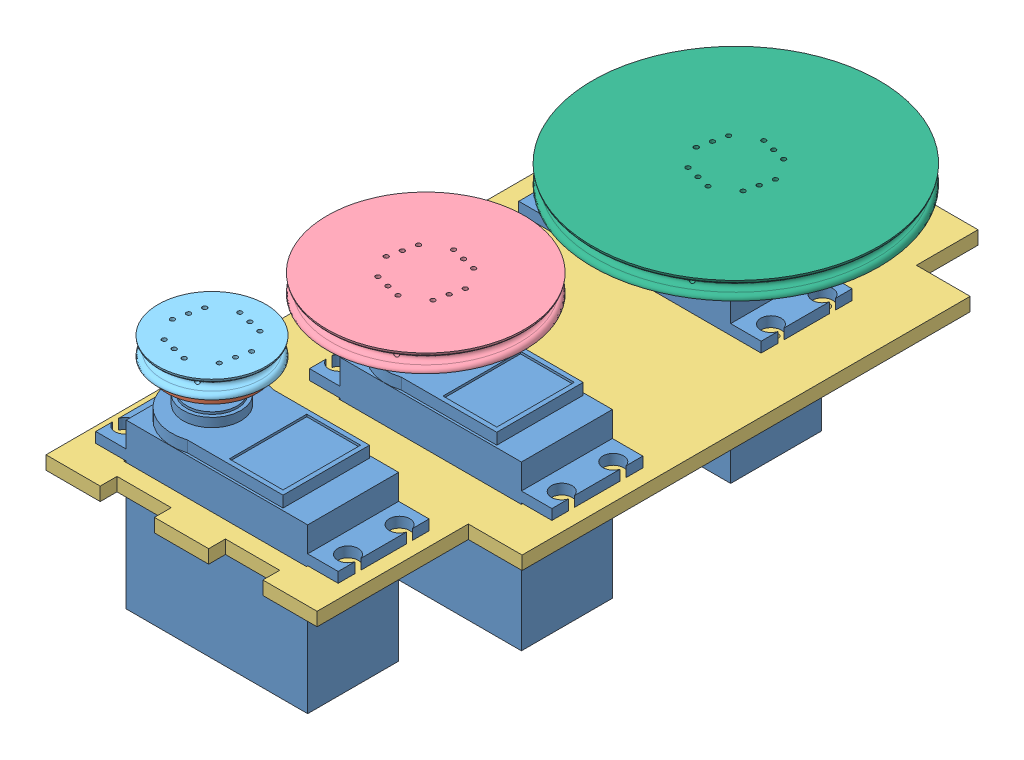
SolidWorks assembly ServoSet, configuration Default. Lengths in mm.
Overall size (82.84 52.3 148.09).
13 component instances, 6 part files, 18 mates.
Components (placement in the parent):
- MG996R-Servo-with-Hub-1: MG996R-Servo-with-Hub [Default] at (-42.4416 98.8668 240.9659) x (0 0 -1) z (1 0 0) size (24.11 48.3 54.1)
  - MG996R-Servo-1: MG996R-Servo [Default] at (29.3026 10.0421 49.0781) size (20.3 45.5 54.1)
  - Servo-Hub-1: Servo-Hub [Default] at (29.3026 56.1421 60.3281) x (0.973354 0 0.229307) z (-0.229307 0 0.973354) size (20.05 5.6 20.05)
- ServoHolderDirect-2: ServoHolderDirect [Default] at (3.7865 137.5089 247.5133) x (-1 0 0) z (0 0 1) size (72.5 3 147.5)
- MG996R-Servo-with-Hub-4: MG996R-Servo-with-Hub [Default] at (64.7146 98.8668 238.0606) x (0 0 1) z (-1 0 0) size (24.11 48.3 54.1)
  - MG996R-Servo-1: MG996R-Servo [Default] at (29.3026 10.0421 49.0781) size (20.3 45.5 54.1)
  - Servo-Hub-1: Servo-Hub [Default] at (29.3026 56.1421 60.3281) x (0.973354 0 0.229307) z (-0.229307 0 0.973354) size (20.05 5.6 20.05)
- MG996R-Servo-with-Hub-5: MG996R-Servo-with-Hub [Default] at (53.0146 98.8668 274.0606) x (0 0 1) z (-1 0 0) size (24.11 48.3 54.1)
  - MG996R-Servo-1: MG996R-Servo [Default] at (29.3026 10.0421 49.0781) size (20.3 45.5 54.1)
  - Servo-Hub-1: Servo-Hub [Default] at (29.3026 56.1421 60.3281) x (0.973354 0 0.229307) z (-0.229307 0 0.973354) size (20.05 5.6 20.05)
- MotorTransmissionMedium-1: MotorTransmissionMedium [Default] at (4.3865 154.2089 267.3633) x (0.973354 0 0.229307) z (0.229307 0 -0.973354) size (44 4 44)
- MotorTransmissionSmall-1: MotorTransmissionSmall [Default] at (-7.3135 154.2089 303.3633) x (0.973354 0 0.229307) z (0.229307 0 -0.973354) size (24 4 24)
- MotorTransmissionLarge-1: MotorTransmissionLarge [Default] at (17.8865 154.2089 211.6633) x (-0.973354 0 -0.229307) z (-0.229307 0 0.973354) size (64 4 64)
Mates (geometry in assembly coordinates):
- Coincident16: coincident anti-aligned: plane of Motor_and_attachmentDirect-4/ServoAttachmentDirect-1 through (4.3865 157.2089 267.3633) normal (0 1 0); plane of MotorTransmissionMedium-1 through (4.3865 157.2089 267.3633) normal (0 -1 0)
- Coincident17: coincident anti-aligned: plane of Motor_and_attachmentDirect-5/ServoAttachmentDirect-1 through (-7.3135 157.2089 303.3633) normal (0 1 0); plane of MotorTransmissionSmall-1 through (-7.3135 157.2089 303.3633) normal (0 -1 0)
- Coincident18: coincident anti-aligned: plane of Motor_and_attachmentDirect-1/ServoAttachmentDirect-1 through (17.8865 157.2089 211.6633) normal (0 1 0); plane of MotorTransmissionLarge-1 through (17.8865 157.2089 211.6633) normal (0 -1 0)
- Concentric38: concentric aligned: cylinder of Motor_and_attachmentDirect-5/ServoAttachmentDirect-1 through (-11.8445 157.2089 309.5132) axis (0 -1 0) radius 0.5; cylinder of MotorTransmissionSmall-1 through (-11.8445 161.2089 309.5132) axis (0 -1 0) radius 0.5
- Concentric39: concentric aligned: cylinder of Motor_and_attachmentDirect-5/ServoAttachmentDirect-1 through (-6.0043 157.2089 310.889) axis (0 -1 0) radius 0.5; cylinder of MotorTransmissionSmall-1 through (-6.0043 161.2089 310.889) axis (0 -1 0) radius 0.5
- Concentric40: concentric aligned: cylinder of Motor_and_attachmentDirect-1/ServoAttachmentDirect-1 through (16.5773 157.2089 204.1376) axis (0 -1 0) radius 0.5; cylinder of MotorTransmissionLarge-1 through (16.5773 161.2089 204.1376) axis (0 -1 0) radius 0.5
- Parallel1: parallel aligned: cylinder of MotorTransmissionLarge-1 through (22.4174 161.2089 205.5134) axis (0 -1 0) radius 0.5; cylinder of Motor_and_attachmentDirect-1/ServoAttachmentDirect-1 through (22.4174 157.2089 205.5134) axis (0 -1 0) radius 0.5
- Concentric41: concentric aligned: cylinder of Motor_and_attachmentDirect-4/ServoAttachmentDirect-1 through (-3.1392 157.2089 268.6725) axis (0 -1 0) radius 0.5; cylinder of MotorTransmissionMedium-1 through (-3.1392 161.2089 268.6725) axis (0 -1 0) radius 0.5
- Concentric42: concentric aligned: cylinder of Motor_and_attachmentDirect-4/ServoAttachmentDirect-1 through (-1.7634 157.2089 262.8323) axis (0 -1 0) radius 0.5; cylinder of MotorTransmissionMedium-1 through (-1.7634 161.2089 262.8323) axis (0 -1 0) radius 0.5
- Coincident51: coincident anti-aligned: plane of MG996R-Servo-with-Hub-1/MG996R-Servo-1 through (26.8865 145.4089 221.8133) normal (0 0 1); plane of ServoHolderDirect-2 through (3.7865 134.5089 221.8133) normal (0 0 -1)
- Coincident52: coincident anti-aligned: plane of MG996R-Servo-with-Hub-1/MG996R-Servo-1 through (-13.6135 145.4089 221.8133) normal (-1 0 0); plane of ServoHolderDirect-2 through (-13.6135 134.5089 247.5133) normal (1 0 0)
- Coincident54: coincident anti-aligned: plane of MG996R-Servo-with-Hub-1/MG996R-Servo-1 through (-20.4135 137.5089 201.5133) normal (0 -1 0); plane of ServoHolderDirect-2 through (3.7865 137.5089 247.5133) normal (0 1 0)
- Coincident55: coincident anti-aligned: plane of ServoHolderDirect-2 through (3.7865 134.5089 257.2133) normal (0 0 1); plane of MG996R-Servo-with-Hub-4/MG996R-Servo-1 through (-4.6135 145.4089 257.2133) normal (0 0 -1)
- Coincident56: coincident anti-aligned: plane of ServoHolderDirect-2 through (-4.6135 134.5089 247.5133) normal (1 0 0); plane of MG996R-Servo-with-Hub-4/MG996R-Servo-1 through (-4.6135 145.4089 257.2133) normal (-1 0 0)
- Coincident57: coincident anti-aligned: plane of ServoHolderDirect-2 through (3.7865 137.5089 247.5133) normal (0 1 0); plane of MG996R-Servo-with-Hub-4/MG996R-Servo-1 through (-11.4135 137.5089 277.5133) normal (0 -1 0)
- Coincident58: coincident anti-aligned: plane of ServoHolderDirect-2 through (3.7865 134.5089 293.2133) normal (0 0 1); plane of MG996R-Servo-with-Hub-5/MG996R-Servo-1 through (-16.3135 145.4089 293.2133) normal (0 0 -1)
- Coincident59: coincident anti-aligned: plane of ServoHolderDirect-2 through (24.1865 134.5089 247.5133) normal (-1 0 0); plane of MG996R-Servo-with-Hub-5/MG996R-Servo-1 through (24.1865 145.4089 293.2133) normal (1 0 0)
- Coincident60: coincident anti-aligned: plane of ServoHolderDirect-2 through (3.7865 137.5089 247.5133) normal (0 1 0); plane of MG996R-Servo-with-Hub-5/MG996R-Servo-1 through (-23.1135 137.5089 313.5133) normal (0 -1 0)
